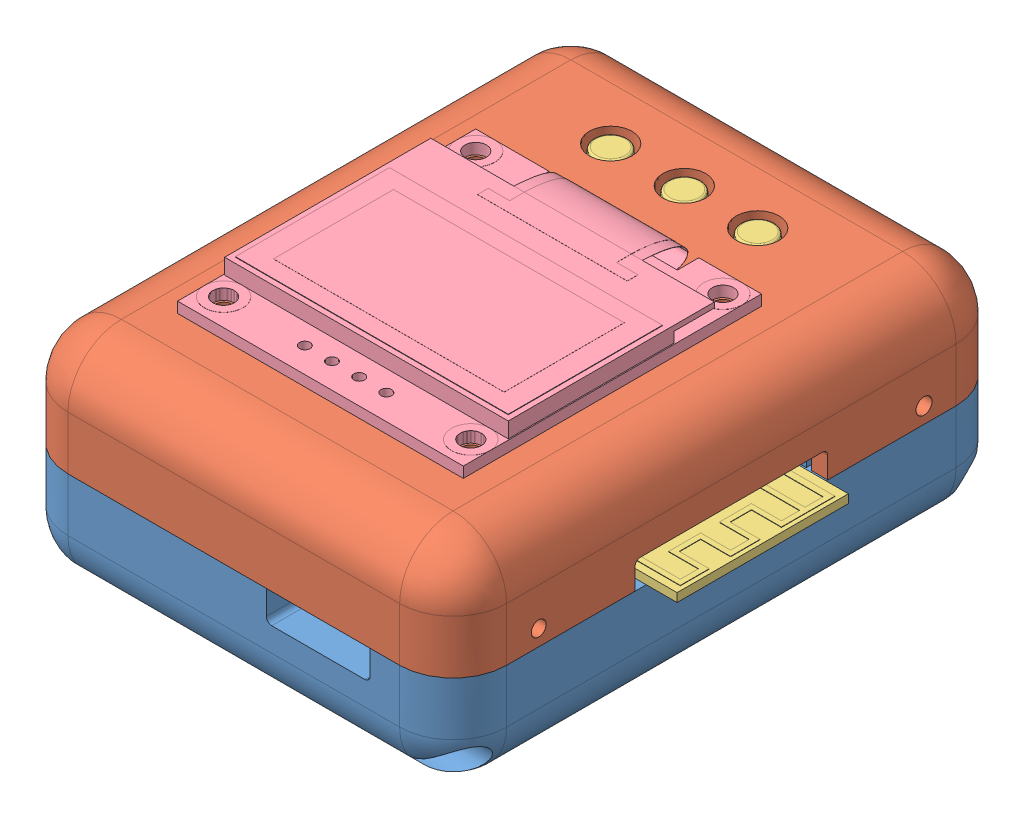
SolidWorks assembly SmartWatch2, configuration Default. Lengths in mm.
Overall size (43.93 22.79 52).
5 component instances, 5 part files, 10 mates.
Components (placement in the parent):
- BottomBox-1: BottomBox [Default] at origin size (41 12.6 52)
- TopBox-2: TopBox [Default] at origin size (41 10 52)
- PCB_SmartWatchV11-2: PCB_SmartWatchV11 [Default] at (49.526 0.0115 -35.079) x (-1 0 0) z (0 1 0) size (41.35 46.1 13.05)
- lcd-1: lcd [Default] at (-34.3304 11.245 8.344) x (-1 0 0) z (0 1 0) size (26.7 28.02 2.98)
- 30100-1: 30100 [Varsayılan] at (-9 -4.9 7) x (0 0 -1) z (0 -1 0) size (14 18 9.5)
Mates (geometry in assembly coordinates):
- Coincident1: coincident anti-aligned: plane of BottomBox-1 through (0 0 0) normal (0 1 0); plane of TopBox-2 through (0 0 0) normal (0 -1 0)
- Coincident2: coincident aligned: plane of BottomBox-1 through (20.5 10 21) normal (1 0 0); plane of TopBox-2 through (20.5 10 21) normal (1 0 0)
- Coincident3: coincident aligned: plane of BottomBox-1 through (-15.5 10 -26) normal (0 0 -1); plane of TopBox-2 through (-15.5 10 -26) normal (0 0 -1)
- ProfileCenter2: profile center = 7.6 mm aligned: plane of BottomBox-1 through (-17.5 -8 21) normal (0 1 0); plane of PCB_SmartWatchV11-2 through (16.5 -0.4 -20.5) normal (0 1 0)
- Coincident5: coincident anti-aligned: plane of TopBox-2 through (0 0 0) normal (1 0 0); plane of assembly through (0 0 0) normal (-1 0 0)
- Coincident6: coincident aligned: plane of lcd-1 through (-13.35 10 17.9) normal (0 0 1); plane of assembly through (0 0 17.9) normal (0 0 1)
- Coincident11: coincident anti-aligned: plane of 30100-1 through (-9 -5.9 7) normal (0 -1 0); plane of assembly through (0 -5.9 0) normal (0 1 0)
- Coincident14: coincident aligned: plane of 30100-1 through (9 -5.9 7) normal (1 0 0); plane of assembly through (9 0 0) normal (1 0 0)
- Coincident15: coincident aligned: plane of 30100-1 through (-9 -5.9 7) normal (0 0 1); plane of assembly through (0 0 7) normal (0 0 1)
- Coincident16: coincident anti-aligned: plane of TopBox-2 through (-15.5 10 21) normal (0 1 0); plane of lcd-1 through (0 10 5.34) normal (0 -1 0)
